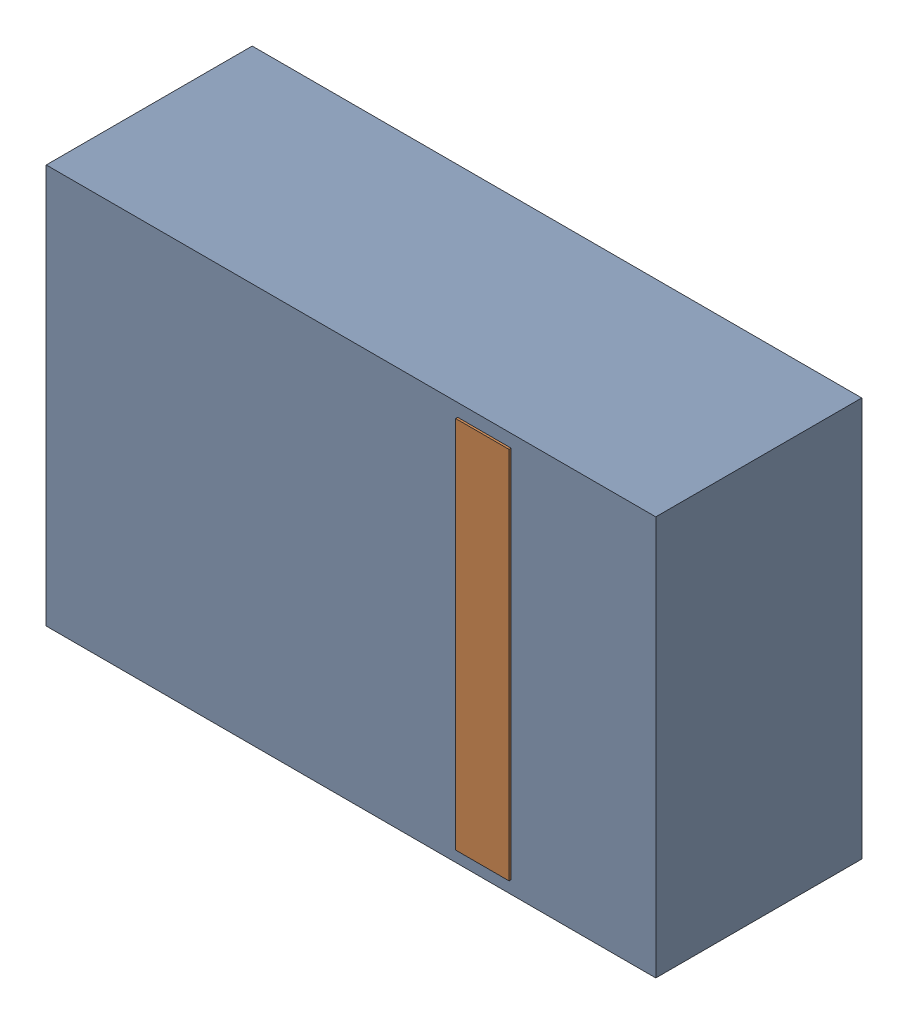
SolidWorks assembly D20, configuration Default. Lengths in mm.
Overall size (2.9 1.9 0.99).
4 component instances, 2 part files, 0 mates.
Components (placement in the parent):
- 905269392-1: 905269392 [Default] at (125.73 63.5 0) size (2.9 1.9 0.98)
  - Extruded_5-1: Extruded_5 [Default] at origin size (2.9 1.9 0.98)
- 905269800-1: 905269800 [Default] at (126.365 63.5 0.95) size (0.25 1.78 0.04)
  - Extruded_6-1: Extruded_6 [Default] at origin size (0.25 1.78 0.04)
